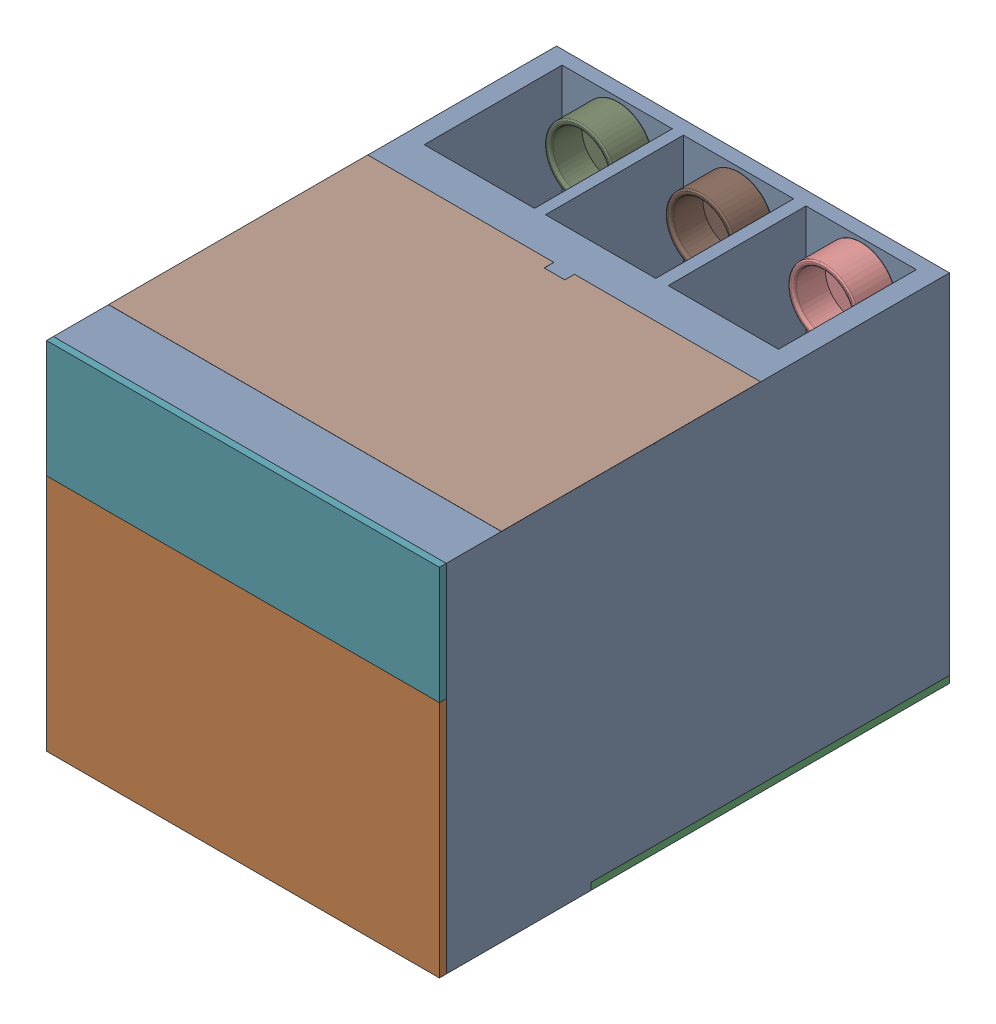
SolidWorks assembly PillZilla, configuration Default. Lengths in mm.
Overall size (285 258.09 370.05).
11 component instances, 7 part files, 18 mates.
Components (placement in the parent):
- part 7 box-1: part 7 box [Default] at (91.0444 -7.7195 81.6739) size (285 258 365)
- part 2 machine box  cap-1: part 2 machine box  cap [Default] at (106.3058 -48.206 451.6739) x (-1 0 0) z (0 0 -1) size (284.9 173 35)
- Part 3 machine box cap-1: Part 3 machine box cap [Default] at (79.7474 -151.2964 254.6742) x (1 0 0) z (0 1 0) size (285 260 25)
- part 6 container-1: part 6 container [Default] at (187.2328 64.1331 191.6739) size (63.5 63.5 220)
- part 6 container-2: part 6 container [Default] at (13.6328 64.1331 191.6739) x (0.999892 0.014666 0) z (0 0 1) size (63.5 63.5 220)
- part 6 container-3: part 6 container [Default] at (100.4328 64.1331 191.6739) x (0.905117 -0.425163 0) z (0 0 1) size (63.5 63.5 220)
- part 1 machine box cap-1: part 1 machine box cap [Default] at (103.9206 96.1217 451.6739) x (-1 0 0) z (0 0 -1) size (285 85 25)
- part 4 front panel cap-3: part 4 front panel cap [Default] at (104.1669 106.7211 293.7909) x (-1 0 0) z (0 -1 0) size (285 188 85)
- part 5  compartment box-3: part 5  compartment box [Default] at (12.8869 78.792 119.785) x (1 0 0) z (0 0 -1) size (50.8 50.8 28)
- part 5  compartment box-4: part 5  compartment box [Default] at (189.334 78.7596 119.7309) x (1 0 0) z (0 0 -1) size (50.8 50.8 28)
- part 5  compartment box-5: part 5  compartment box [Default] at (100.3672 78.4133 119.6744) x (1 0 0) z (0 0 -1) size (50.8 50.8 28)
Mates (geometry in assembly coordinates):
- Coincident1: coincident anti-aligned: plane of part 7 box-1 through (237.9328 16.6331 346.6739) normal (-1 0 0); plane of part 2 machine box  cap-1 through (237.9328 16.6331 416.6739) normal (1 0 0)
- Coincident2: coincident anti-aligned: plane of part 7 box-1 through (-37.0672 -146.3669 346.6739) normal (0 1 0); plane of part 2 machine box  cap-1 through (237.9328 -146.3669 416.6739) normal (0 -1 0)
- Parallel1: parallel anti-aligned: plane of part 7 box-1 through (-37.0672 16.6331 346.6739) normal (1 0 0); plane of part 2 machine box  cap-1 through (-36.9672 16.6331 416.6739) normal (-1 0 0)
- Coincident5: coincident anti-aligned: plane of part 7 box-1 through (91.0444 -7.7195 446.6739) normal (0 0 1); plane of part 2 machine box  cap-1 through (106.3058 -48.206 446.6739) normal (0 0 -1)
- Parallel9: parallel anti-aligned: plane of part 7 box-1 through (-42.0672 -146.3669 341.6739) normal (0 0 -1); plane of Part 3 machine box cap-1 through (-42.0672 -146.2964 341.6265) normal (0 0 1)
- Coincident33: coincident aligned: plane of part 7 box-1 through (-42.0672 106.6331 446.6739) normal (-1 0 0); plane of Part 3 machine box cap-1 through (-42.0672 -146.2964 81.6265) normal (-1 0 0)
- Concentric1: concentric aligned: circle of part 7 box-1; cylinder of part 6 container-1 through (187.2328 64.1331 411.6739) axis (0 0 -1) radius 29.75
- Coincident34: coincident aligned: plane of part 7 box-1 through (91.0444 -7.7195 411.6739) normal (0 0 1); plane of part 6 container-1 through (187.2328 64.1331 411.6739) normal (0 0 1)
- Concentric2: concentric anti-aligned: cylinder of part 7 box-1 through (100.4328 64.1331 135.6739) axis (0 0 1) radius 31.75; cylinder of part 6 container-3 through (100.4328 64.1331 411.6739) axis (0 0 -1) radius 29.75
- Concentric3: concentric anti-aligned: cylinder of part 7 box-1 through (13.6328 64.1331 135.6739) axis (0 0 1) radius 31.75; cylinder of part 6 container-2 through (13.6328 64.1331 411.6739) axis (0 0 -1) radius 31.75
- Coincident48: coincident anti-aligned: plane of part 7 box-1 through (-37.0672 101.6331 411.6739) normal (1 0 0); plane of part 1 machine box cap-1 through (-37.0672 101.6331 426.6739) normal (-1 0 0)
- Coincident49: coincident anti-aligned: plane of part 7 box-1 through (91.0444 -7.7195 446.6739) normal (0 0 1); plane of part 1 machine box cap-1 through (103.9206 96.1217 446.6739) normal (0 0 -1)
- Coincident66: coincident aligned: plane of part 7 box-1 through (242.9328 106.6331 446.6739) normal (1 0 0); plane of part 4 front panel cap-3 through (242.9328 101.7211 218.6739) normal (1 0 0)
- Coincident67: coincident anti-aligned: plane of part 7 box-1 through (-37.0672 26.6331 406.6739) normal (0 0 -1); plane of part 4 front panel cap-3 through (242.9328 101.7211 406.6739) normal (0 0 1)
- Coincident69: coincident aligned: plane of part 7 box-1 through (91.0444 -7.7195 411.6739) normal (0 0 1); plane of part 6 container-2 through (13.6328 64.1331 411.6739) normal (0 0 1)
- Coincident70: coincident aligned: plane of part 7 box-1 through (91.0444 -7.7195 411.6739) normal (0 0 1); plane of part 6 container-2 through (13.6328 64.1331 411.6739) normal (0 0 1)
- Coincident71: coincident aligned: plane of part 7 box-1 through (91.0444 -7.7195 411.6739) normal (0 0 1); plane of part 6 container-3 through (100.4328 64.1331 411.6739) normal (0 0 1)
- Coincident72: coincident aligned: plane of part 7 box-1 through (91.0444 -7.7195 411.6739) normal (0 0 1); plane of part 6 container-1 through (187.2328 64.1331 411.6739) normal (0 0 1)
